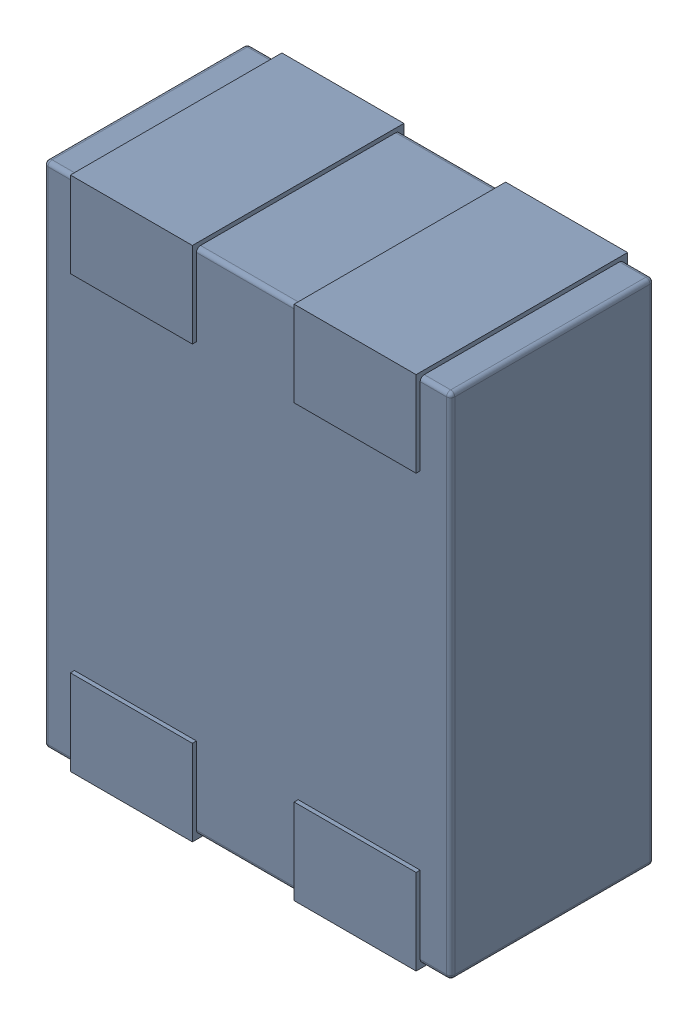
SolidWorks assembly L8, configuration Défaut. Lengths in mm.
Overall size (1 1.27 0.52).
4 component instances, 1 part files, 0 mates.
Components (placement in the parent):
- MCZ1210DH900L2TA0G-1: MCZ1210DH900L2TA0G [Défaut] at (42.2967 -40.5265 -1.6) x (-1 0 0) z (0 0 1) size (1 1.27 0.52)
  - 3D_PCB1_2021-12-30 (1).step-1: 3D_PCB1_2021-12-30 (1).step [Défaut] at origin size (1 1.27 0.52)
    - a3ec64f90eb5404ebd79eca0046a794a.step-1: a3ec64f90eb5404ebd79eca0046a794a.step [Défaut] at (5.0419 -6.8961 1.6) size (1 1.27 0.52)
      - SOLID.step_650-1: SOLID.step_650 [Défaut] at origin size (1 1.27 0.52)
